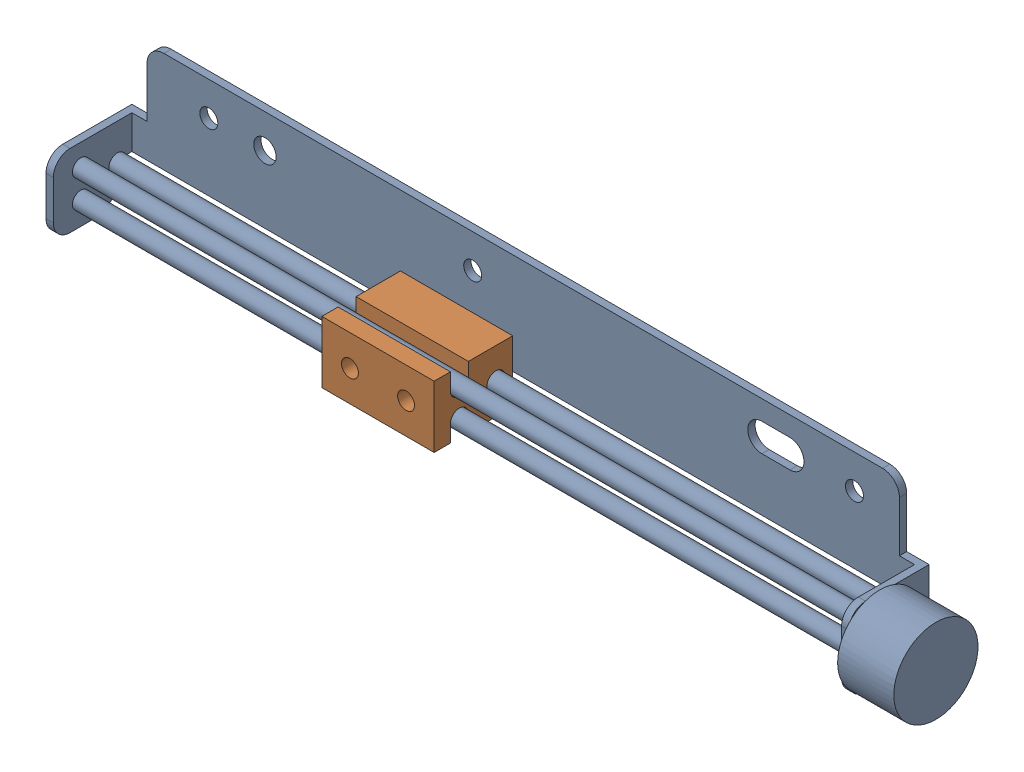
SolidWorks assembly 电机, configuration 默认. Lengths in mm.
Overall size (152 26.5 16.3).
2 component instances, 2 part files, 4 mates.
Components (placement in the parent):
- 步进电机-1: 步进电机 [默认] at (-15.9867 -2.9189 -6.85) size (152 26.5 16.3)
- 滑块-2: 滑块 [默认] at (-27.856 -2.9189 7.15) size (20 11 14)
Mates (geometry in assembly coordinates):
- 同心4: concentric anti-aligned: circle of 步进电机-1; circle of 滑块-2
- 同心5: concentric anti-aligned: circle of 步进电机-1; circle of 滑块-2
- 同心6: concentric anti-aligned: circle of 步进电机-1; circle of 滑块-2
- LimitDistance1: limit distance = 71.5693 mm anti-aligned: plane of 滑块-2 through (-17.856 2.5811 -6.85) normal (1 0 0); plane of 步进电机-1 through (53.7133 3.0811 6.15) normal (-1 0 0)
